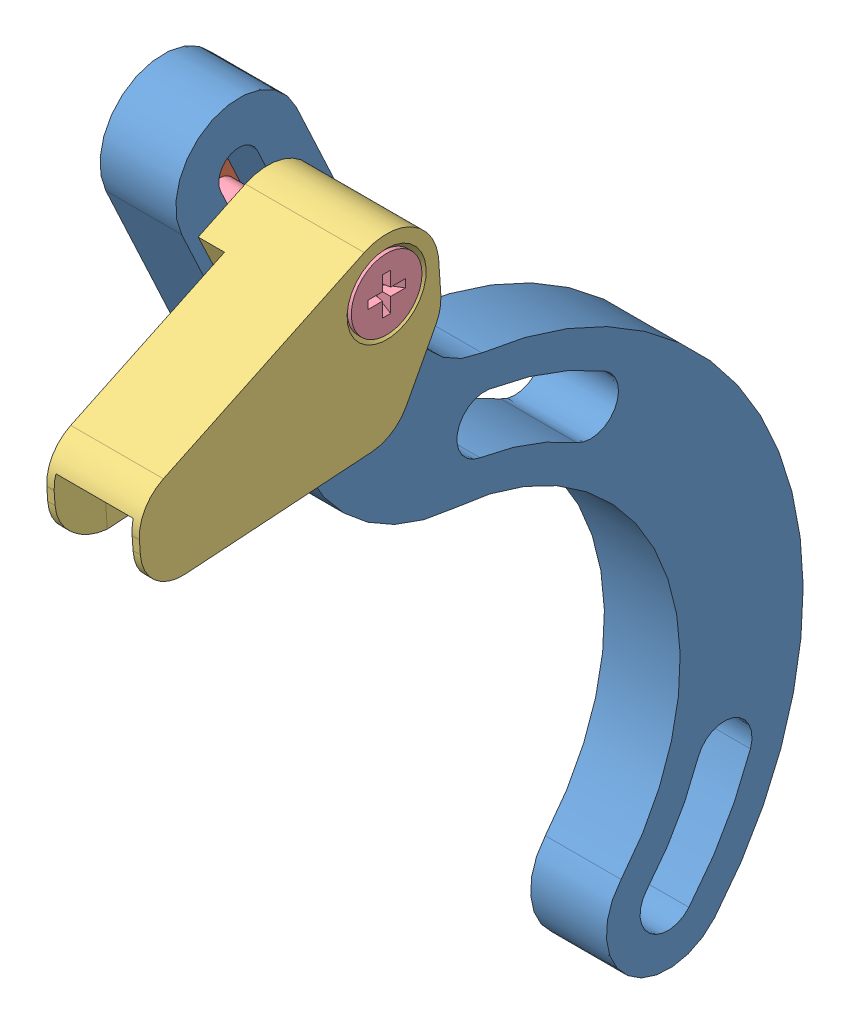
SolidWorks assembly chainguide, configuration Default. Lengths in mm.
Overall size (25 115.13 93.94).
4 component instances, 4 part files, 6 mates.
Components (placement in the parent):
- chainguide_Bottom-1: chainguide_Bottom [Default] at origin size (9 115.13 74.51)
- m4_nut-1: m4_nut [Default] at (1.69 69.2543 19.7906) x (0 -0.906308 -0.422618) z (0 -0.422618 0.906308) size (10.76 3.36 9.32)
- guide-2: guide [Default] at (12.12 69.2543 19.7906) x (1 0 0) z (0 -0.067056 0.997749) size (14.12 21.4 36.2)
- flat head screw_am-3: flat head screw_am [B18.6.7M - M4 x 0.7 x 25 Type I Cross Recessed FHMS --25N] at (23.12 69.2543 19.7906) x (-1 0 0) z (0 0 -1) size (25 8.4 8.4)
Mates (geometry in assembly coordinates):
- Coincident1: coincident anti-aligned: plane of chainguide_Bottom-1 through (3.25 0 0) normal (-1 0 0); plane of m4_nut-1 through (3.25 69.2543 19.7906) normal (1 0 0)
- Parallel1: parallel: line of chainguide_Bottom-1 through (3.25 64.8228 12.4831) axis (0 0.906308 0.422618); plane of m4_nut-1 through (3.25 68.7853 14.4302) normal (0 0.422618 -0.906308)
- Slot1: slot aligned: cylinder of m4_nut-1 through (0.13 69.2543 19.7906) axis (-1 0 0) radius 1.65; plane of chainguide_Bottom-1 through (9 5.8033 -12.4452) normal (0 -0.422618 0.906308); cylinder of chainguide_Bottom-1 through (9 76.5912 23.2119) axis (-1 0 0) radius 2.4
- Concentric1: concentric aligned: circle of m4_nut-1; circle of guide-2
- Coincident2: coincident anti-aligned: plane of chainguide_Bottom-1 through (9 0 0) normal (1 0 0); plane of guide-2 through (9 69.2543 19.7906) normal (-1 0 0)
- Coincident3: coincident aligned: cone of guide-2 through (23.12 69.2543 19.7906) axis (-1 0 0); cone of flat head screw_am-3 through (22.62 69.2543 19.7906) axis (-1 0 0)
